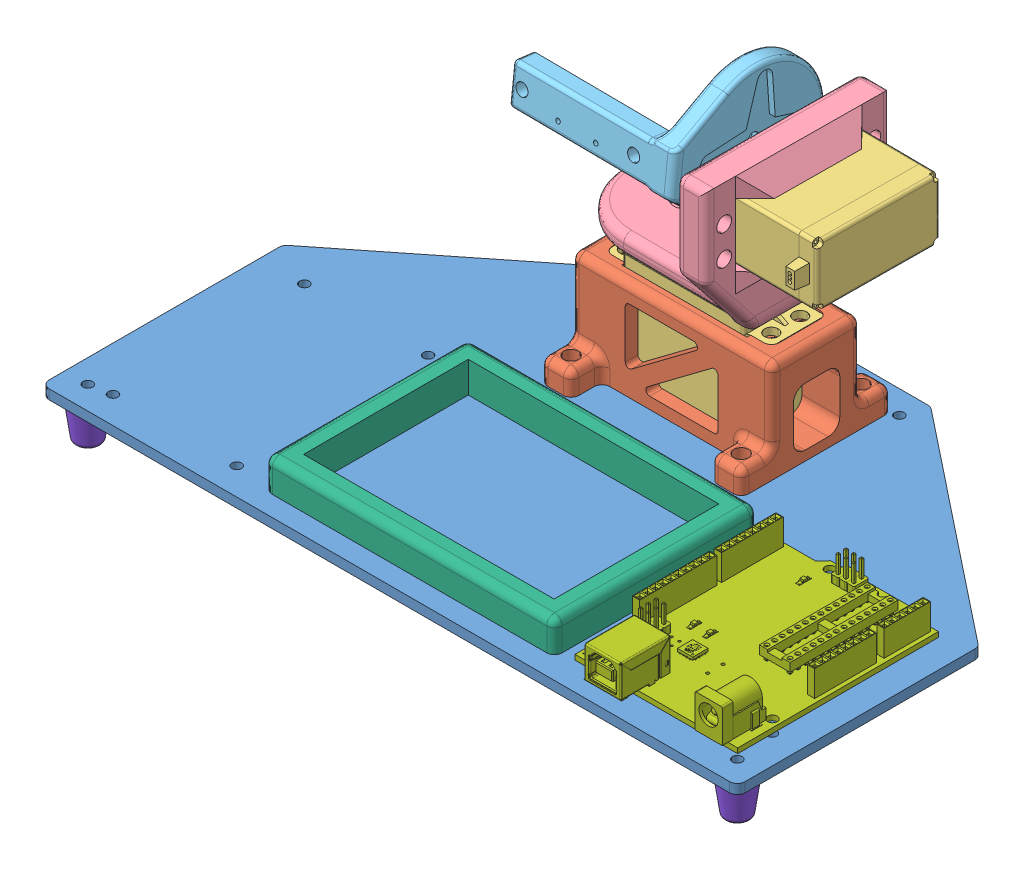
SolidWorks assembly Pan-Tilt Mechanism, configuration Default. Lengths in mm.
Overall size (228.6 120.85 139.7).
12 component instances, 8 part files, 27 mates.
Components (placement in the parent):
- Pan-Tilt Base-1: Pan-Tilt Base [Default] at (-115.4444 -2.3346 91.4179) size (228.6 3.17 139.7)
- Pan Servo Mount-1: Pan Servo Mount [Default] at (-1.1444 0.8404 -15.8971) size (66.04 32.38 49.53)
- Servo-1: Servo [Default] at (-1.7283 -2.7555 -15.6471) size (55.4 47.6 20)
- Tilt Base2-1: Tilt Base2 [Default] at (-10.7431 45.9675 -15.6471) x (0.999962 0 0.008671) z (-0.008671 0 0.999962) size (73.96 51.99 60.24)
- Servo-2: Servo [Default] at (62.29 81.2695 -5.7981) x (-0.008671 0 0.999962) z (0 -1 0) size (55.4 47.6 20)
- Sensor Holder-1: Sensor Holder [Default] at (-18.3432 84.3621 12.3336) x (-0.999962 0 -0.008671) z (0.008618 -0.110387 -0.993851) size (53.98 43.18 49.61)
- Breadboard Mount-1: Breadboard Mount [Default] at (-1.1444 0.8404 51.4129) size (95.25 10.16 66.8)
- arduino uno-1: arduino uno [Default] at (106.5029 4.9904 84.6401) x (0.999998 0 -0.001956) z (0.001956 0 0.999998) size (53.34 15.25 74.93)
- Base Plate Stand-1: Base Plate Stand [Default] at (-36.5889 -2.3346 -40.6621) size (11.43 12.7 11.43)
- Base Plate Stand-2: Base Plate Stand [Default] at (-107.8244 -2.3346 83.7979) size (11.43 12.7 11.43)
- Base Plate Stand-3: Base Plate Stand [Default] at (34.3001 -2.3346 -40.6621) size (11.43 12.7 11.43)
- Base Plate Stand-4: Base Plate Stand [Default] at (105.5356 -2.3346 83.7979) size (11.43 12.7 11.43)
Mates (geometry in assembly coordinates):
- Coincident1: coincident anti-aligned: plane of Pan-Tilt Base-1 through (-115.4444 0.8404 91.4179) normal (0 1 0); plane of Pan Servo Mount-1 through (-1.1444 0.8404 -15.8971) normal (0 -1 0)
- Coincident2: coincident anti-aligned: plane of Pan Servo Mount-1 through (-26.0364 30.6854 -9.2296) normal (0 1 0); plane of Servo-1 through (-29.4283 30.6854 -6.6471) normal (0 -1 0)
- Concentric4: concentric aligned: cylinder of Pan Servo Mount-1 through (-25.4444 20.5254 -10.8971) axis (0 1 0) radius 2.413; cylinder of Servo-1 through (-25.4444 24.3215 -10.8971) axis (0 1 0) radius 2.25
- Parallel1: parallel aligned: plane of Pan Servo Mount-1 through (-34.1644 33.2254 -30.5021) normal (0 0 -1); plane of Servo-1 through (-21.7283 36.7445 -25.6471) normal (0 0 -1)
- Coincident3: coincident anti-aligned: plane of Tilt Base2-1 through (28.9302 45.9675 -15.3031) normal (-0.999962 0 -0.008671); plane of Servo-2 through (28.6101 72.2695 21.6109) normal (0.999962 0 0.008671)
- Concentric5: concentric aligned: cylinder of Tilt Base2-1 through (36.6757 86.0195 -29.7372) axis (-0.999962 0 -0.008671) radius 2.413; cylinder of Servo-2 through (35.4197 86.0195 -29.7481) axis (-0.999962 0 -0.008671) radius 2.25
- Parallel2: parallel aligned: plane of Tilt Base2-1 through (-10.7431 97.7835 -15.6471) normal (0 1 0); plane of Servo-2 through (22.9649 91.2695 -26.1399) normal (0 1 0)
- Concentric6: concentric aligned: circle of Servo-2; cylinder of Sensor Holder-1 through (13.647 81.2695 -15.235) axis (-0.999962 0 -0.008671) radius 1.5875
- Concentric7: concentric aligned: circle of Servo-1; cylinder of Tilt Base2-1 through (-10.7431 52.3175 -15.6471) axis (0 -1 0) radius 1.5875
- Distance1: distance = 6.223 mm anti-aligned: plane of Sensor Holder-1 through (13.7402 86.619 -25.9746) normal (0.999962 0 0.008671); plane of Servo-2 through (19.9518 72.5195 -24.637) normal (-0.999962 0 -0.008671)
- Distance2: distance = 6.223 mm anti-aligned: plane of Tilt Base2-1 through (-10.7431 45.9675 -15.6471) normal (0 -1 0); plane of Servo-1 through (-20.1994 39.7445 -6.8971) normal (0 1 0)
- DELETE: parallel: line of Pan-Tilt Base-1 through (-115.4444 0.8404 27.9179) axis (1 0 0); plane of Sensor Holder-1
- Concentric8: concentric aligned: cylinder of Pan-Tilt Base-1 through (26.7956 0.8404 3.7879) axis (0 -1 0) radius 1.778; cylinder of Pan Servo Mount-1 through (26.7956 33.2254 3.7879) axis (0 -1 0) radius 2.3876
- Concentric9: concentric aligned: cylinder of Pan-Tilt Base-1 through (-29.0844 0.8404 -35.5821) axis (0 -1 0) radius 1.778; cylinder of Pan Servo Mount-1 through (-29.0844 33.2254 -35.5821) axis (0 -1 0) radius 2.3876
- Coincident5: coincident anti-aligned: plane of Pan-Tilt Base-1 through (-115.4444 0.8404 91.4179) normal (0 1 0); plane of Breadboard Mount-1 through (-1.1444 0.8404 51.4129) normal (0 -1 0)
- Concentric10: concentric anti-aligned: circle of Pan-Tilt Base-1; cylinder of Breadboard Mount-1 through (-45.5944 8.4604 81.8929) axis (0 -1 0) radius 1.9939
- Concentric11: concentric anti-aligned: cylinder of Pan-Tilt Base-1 through (43.3056 -2.3346 20.9329) axis (0 1 0) radius 1.524; cylinder of Breadboard Mount-1 through (43.3056 8.4604 20.9329) axis (0 -1 0) radius 1.8669
- Concentric13: concentric aligned: circle of Pan-Tilt Base-1; circle of arduino uno-1
- Coincident10: coincident anti-aligned: plane of Pan-Tilt Base-1 through (-115.4444 0.8404 91.4179) normal (0 1 0); plane of arduino uno-1 through (62.2334 0.8404 79.7966) normal (0 -1 0)
- Coincident11: coincident: plane of Pan-Tilt Base-1 through (-115.4444 -2.3346 91.4179) normal (0 -1 0); plane of Base Plate Stand-3 through (34.3001 -2.3346 -40.6621) normal (0 1 0)
- Concentric14: concentric aligned: circle of Pan-Tilt Base-1; circle of Base Plate Stand-3
- Coincident12: coincident: plane of Pan-Tilt Base-1 through (-115.4444 -2.3346 91.4179) normal (0 -1 0); plane of Base Plate Stand-1 through (-36.5889 -2.3346 -40.6621) normal (0 1 0)
- Concentric15: concentric anti-aligned: cylinder of Pan-Tilt Base-1 through (-36.5889 -2.3346 -40.6621) axis (0 1 0) radius 1.5875; circle of Base Plate Stand-1
- Concentric16: concentric: cylinder of Pan-Tilt Base-1 through (-107.8244 -2.3346 83.7979) axis (0 1 0) radius 1.5875; circle of Base Plate Stand-2
- Coincident13: coincident anti-aligned: plane of Pan-Tilt Base-1 through (-115.4444 -2.3346 91.4179) normal (0 -1 0); plane of Base Plate Stand-2 through (-107.8244 -2.3346 83.7979) normal (0 1 0)
- Coincident14: coincident: plane of Pan-Tilt Base-1 through (-115.4444 -2.3346 91.4179) normal (0 -1 0); plane of Base Plate Stand-4 through (105.5356 -2.3346 83.7979) normal (0 1 0)
- Concentric17: concentric anti-aligned: cylinder of Pan-Tilt Base-1 through (105.5356 -2.3346 83.7979) axis (0 1 0) radius 1.5875; circle of Base Plate Stand-4
